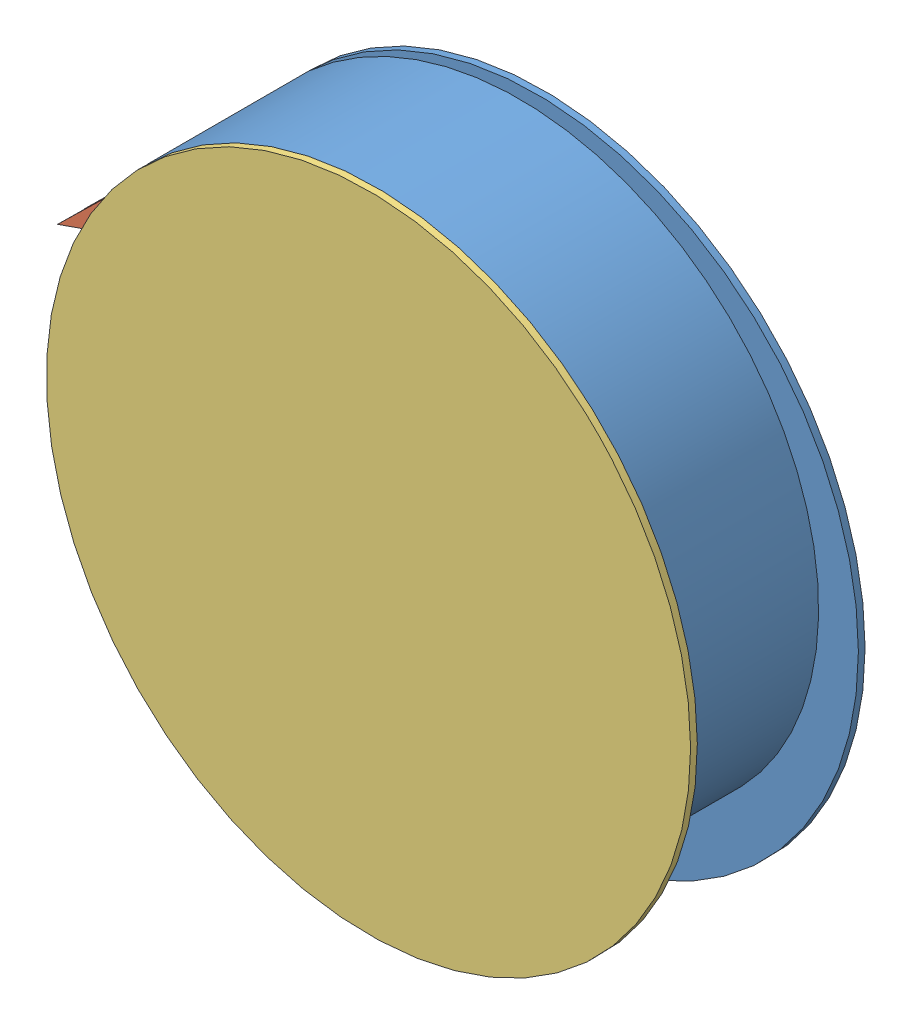
SolidWorks assembly Assembly, configuration Default. Lengths in mm.
Overall size (431.02 431.02 161.5).
4 component instances, 4 part files, 7 mates.
Components (placement in the parent):
- Mesh-1: Mesh [Default] at (143.9181 177.9711 168.6937) size (304.8 304.8 79.38)
- Cutter-1: Cutter [Default] at (141.7008 180.2436 168.6937) x (-0.715725 -0.698383 0) z (-0.698383 0.715725 0) size (64.41 76.2 6.35)
- Side_Wall-3: Side_Wall [Default] at (143.9181 177.9711 248.0687) x (0.715725 0.698383 0) z (0 0 -1) size (304.8 304.8 3.17)
- Redline-1: Redline [Default] at (143.9181 177.9711 161.5187) x (0 0 -1) z (0.923728 0.383049 0) size (87.75 44.3 43.54)
Mates (geometry in assembly coordinates):
- Coincident3: coincident anti-aligned: plane of Mesh-1 through (73.106 248.6051 244.8937) normal (0 0 1); plane of Side_Wall-3 through (143.9181 177.9711 244.8937) normal (0 0 -1)
- Concentric3: concentric aligned: cylinder of Mesh-1 through (143.9181 177.9711 165.5187) axis (0 0 1) radius 152.4; cylinder of Side_Wall-3 through (143.9181 177.9711 244.8937) axis (0 0 1) radius 152.4
- Distance1: distance = 0.3969 mm anti-aligned: plane of Cutter-1 through (141.7008 180.2436 244.8937) normal (0 0 1); plane of Side_Wall-3 through (143.9181 177.9711 245.2906) normal (0 0 -1)
- Coincident5: coincident anti-aligned: plane of Cutter-1 through (39.702 284.7751 244.8937) normal (-0.698383 0.715725 0); plane of Side_Wall-3 through (-44.517 202.5968 245.2906) normal (0.698383 -0.715725 0)
- Coincident6: coincident anti-aligned: plane of Cutter-1 through (39.702 284.7751 244.8937) normal (0.715725 0.698383 0); plane of Side_Wall-3 through (39.702 284.7751 245.2906) normal (-0.715725 -0.698383 0)
- Coincident7: coincident aligned: circle of Mesh-1; plane of Redline-1 through (143.9181 177.9711 165.5187) normal (0 0 1)
- Concentric4: concentric aligned: circle of Mesh-1; cylinder of Redline-1 through (143.9181 177.9711 161.5187) axis (0 0 1) radius 2.5
